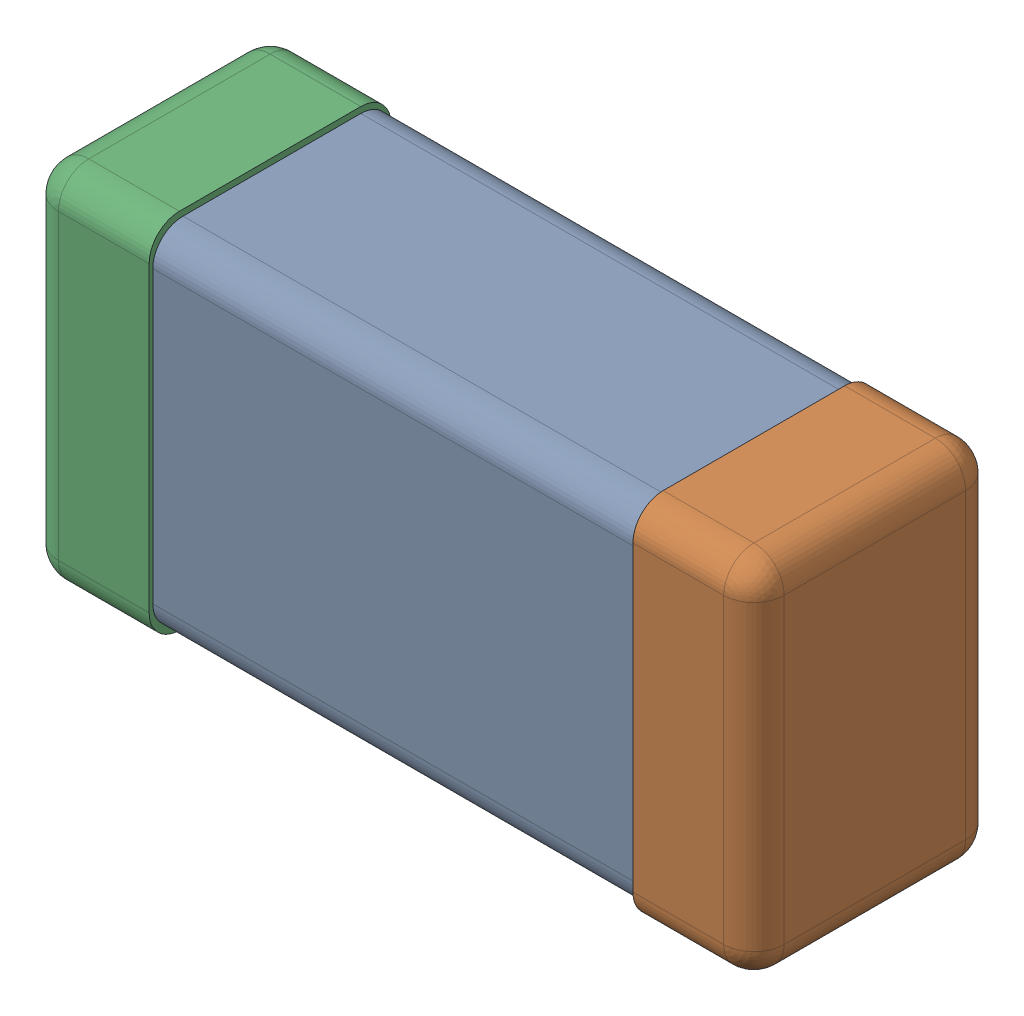
SolidWorks assembly C0201_020_4, configuration Standard. Lengths in mm.
Overall size (0.6 0.3 0.2).
4 component instances, 3 part files, 0 mates.
Components (placement in the parent):
- C0201_020_5-1: C0201_020_5 [Standard] at origin size (0.6 0.3 0.2)
  - Part 3_2-1: Part 3_2 [Standard] at (0 0 -7.3015) size (0.5 0.29 0.2)
  - Part 2_2-1: Part 2_2 [Standard] at (0 0 -7.3) size (0.1 0.3 0.2)
  - Part 1_2-1: Part 1_2 [Standard] at (0 0 -7.3) size (0.1 0.3 0.2)
